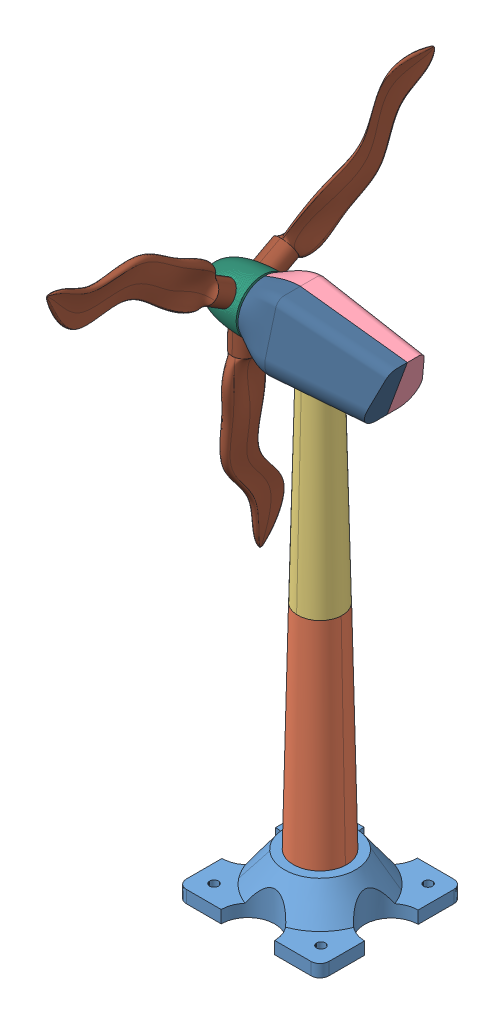
SolidWorks assembly Wind turbine assembly III (INTERNAL RESULT) , configuration Default. Lengths in mm.
Overall size (140.98 456.4 306.35).
17 component instances, 11 part files, 0 mates.
Components (placement in the parent):
- Wind turbine assembly MARC2(cordinate).STEP-1: Wind turbine assembly MARC2(cordinate).STEP [Default] at origin size (140.98 456.4 306.35)
  - base.STEP-1: base.STEP [Default] at (78.4995 -345.44 -0.2668) x (-0.000714 0 1) z (-1 0 -0.000714) size (101.6 30.48 101.6)
  - Wind turbine lower mast.STEP-1: Wind turbine lower mast.STEP [Default] at (78.4995 -327.66 -0.2668) x (0 1 0) z (0.998658 0 0.051782) size (165.1 38.1 38.1)
  - Wind turbine upper mast.STEP-1: Wind turbine upper mast.STEP [Default] at (78.74 -175.26 0) x (0 1 0) z (-0.998658 0 -0.051782) size (152.4 31.75 31.75)
  - nacelle.STEP-1: nacelle.STEP [Default] at (64.77 0 0) x (0 0 1) z (-1 0 0) size (25.51 48.27 101.62)
  - connecting rod.STEP-1: connecting rod.STEP [Default] at (78.74 -29.21 0) x (-0.653528 0 0.756902) z (-0.756902 0 -0.653528) size (9.53 38.1 9.53)
  - Turbine Hub.STEP-1: Turbine Hub.STEP [Default] x (0 -0.031407 -0.999507) z (-1 0 0) size (41.13 38.1 38.1)
  - Turbine Hub.STEP-2: Turbine Hub.STEP [Default] x (0 0.881302 0.472554) z (-1 0 0) size (41.13 38.1 38.1)
  - Turbine Hub.STEP-3: Turbine Hub.STEP [Default] x (0 -0.849895 0.526953) z (-1 0 0) size (41.13 38.1 38.1)
  - 2780T350_HIGH-LOAD BEARING_2780T35.STEP-1: 2780T350_HIGH-LOAD BEARING_2780T35.STEP [Default] at (64.9287 0 0) x (0 0.911809 0.410615) z (-1 0 0) size (23.02 23.02 7.94)
  - 2780T350_HIGH-LOAD BEARING_2780T35.STEP-2: 2780T350_HIGH-LOAD BEARING_2780T35.STEP [Default] at (109.3787 0 0) x (0 -0.378851 0.925458) z (-1 0 0) size (23.02 23.02 7.94)
  - Turbine main shaft.STEP-1: Turbine main shaft.STEP [Default] at (73.025 0 0) x (0 -0.627713 -0.778445) z (0 -0.778445 0.627713) size (9.53 95.25 9.53)
  - 98408A134_SIDE-MOUNT EXTERNAL RETAINING RING  E-STYLE_98408A134.STEP-1: 98408A134_SIDE-MOUNT EXTERNAL RETAINING RING  E-STYLE_98408A134.STEP [Default] at (116.9919 0 0) size (0.89 16.76 15.36)
  - Mirrornacelle.STEP-1: Mirrornacelle.STEP [Default] at (64.77 0 0) x (0 0 -1) z (1 0 0) size (25.53 48.36 101.62)
  - rundwa wing(1).STEP-1: rundwa wing(1).STEP [Default] at (25.4 4.0154 6.4762) x (1 0 0) z (0 -0.849895 0.526953) size (19.03 151.58 60.38)
  - rundwa wing(1).STEP-2: rundwa wing(1).STEP [Default] at (25.4 3.6009 -6.7155) x (1 0 0) z (0 0.881302 0.472554) size (19.03 151.58 60.38)
  - rundwa wing(1).STEP-3: rundwa wing(1).STEP [Default] at (25.4 -7.6162 0.2393) x (1 0 0) z (0 -0.031407 -0.999507) size (19.03 151.58 60.38)
